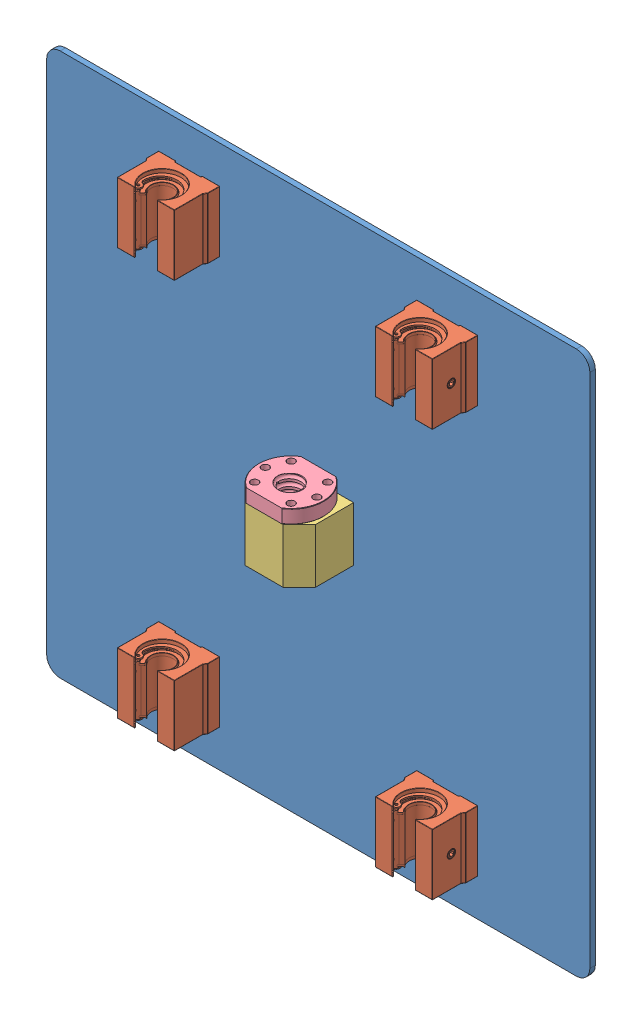
SolidWorks assembly Стол, configuration По умолчанию. Lengths in mm.
Overall size (400 400 44).
7 component instances, 4 part files, 12 mates.
Components (placement in the parent):
- Плита стола-1: Плита стола [По умолчанию] at (-52.7289 -0.1217 50.8505) size (400 400 4)
- SBR16UU-1: SBR16UU [По умолчанию] at (-147.7289 149.8783 74.8505) x (1 0 0) z (0 -1 0) size (45 32 45)
- SBR16UU-2: SBR16UU [По умолчанию] at (-147.7289 -150.1217 74.8505) x (1 0 0) z (0 -1 0) size (45 32 45)
- SBR16UU-3: SBR16UU [По умолчанию] at (42.2711 149.8783 74.8505) x (-1 0 0) z (0 1 0) size (45 32 45)
- SBR16UU-4: SBR16UU [По умолчанию] at (42.2711 -150.1217 74.8505) x (-1 0 0) z (0 1 0) size (45 32 45)
- bsh16-1: bsh16 [По умолчанию] at (-46.8326 19.8783 87.6733) x (1 0 0) z (0 -1 0) size (52 40 40)
- RM1605-1: RM1605 [RM1605] at (-52.7289 29.8783 74.8505) x (0 0 -1) z (0 1 0) size (40 48 48.86)
Mates (geometry in assembly coordinates):
- Концентричный1: concentric anti-aligned: cylinder of Плита стола-1 through (-163.7289 164.8783 54.8505) axis (0 0 1) radius 2.75; cylinder of SBR16UU-1 through (-163.7289 164.8783 54.8505) axis (0 0 -1) radius 2.1
- Концентричный2: concentric anti-aligned: cylinder of Плита стола-1 through (-131.7289 134.8783 54.8505) axis (0 0 1) radius 2.75; cylinder of SBR16UU-1 through (-131.7289 134.8783 54.8505) axis (0 0 -1) radius 2.1
- Совпадение1: coincident anti-aligned: plane of Плита стола-1 through (-52.7289 -0.1217 54.8505) normal (0 0 1); plane of SBR16UU-1 through (-170.2289 127.3783 54.8505) normal (0 0 -1)
- Концентричный3: concentric anti-aligned: cylinder of Плита стола-1 through (-131.7289 -165.1217 54.8505) axis (0 0 1) radius 2.75; cylinder of SBR16UU-2 through (-131.7289 -165.1217 54.8505) axis (0 0 -1) radius 2.1
- Концентричный4: concentric anti-aligned: cylinder of Плита стола-1 through (-163.7289 -165.1217 54.8505) axis (0 0 1) radius 2.75; cylinder of SBR16UU-2 through (-163.7289 -165.1217 54.8505) axis (0 0 -1) radius 2.1
- Совпадение2: coincident anti-aligned: plane of Плита стола-1 through (-52.7289 -0.1217 54.8505) normal (0 0 1); plane of SBR16UU-2 through (-170.2289 -172.6217 54.8505) normal (0 0 -1)
- Концентричный5: concentric: cylinder of Плита стола-1 through (-32.7289 11.8783 54.8505) axis (0 0 1) radius 2.75; cylinder of bsh16-1 through (-32.7289 11.8783 66.8505) axis (0 0 -1) radius 2.1
- Концентричный6: concentric: cylinder of Плита стола-1 through (-72.7289 -12.1217 54.8505) axis (0 0 1) radius 2.75; cylinder of bsh16-1 through (-72.7289 -12.1217 66.8505) axis (0 0 -1) radius 2.1
- Совпадение3: coincident anti-aligned: plane of Плита стола-1 through (-52.7289 -0.1217 54.8505) normal (0 0 1); plane of bsh16-1 through (-78.7289 -20.1217 54.8505) normal (0 0 -1)
- Концентричный7: concentric: cylinder of bsh16-1 through (-52.7289 -19.1217 74.8505) axis (0 1 0) radius 14; cylinder of RM1605-1 through (-52.7289 182.0367 74.8505) axis (0 -1 0) radius 13.9
- Концентричный8: concentric: cylinder of bsh16-1 through (-39.2938 9.8783 61.4155) axis (0 1 0) radius 2.1; cylinder of RM1605-1 through (-39.2938 224.0367 61.4155) axis (0 1 0) radius 2.75
- Совпадение4: coincident anti-aligned: plane of bsh16-1 through (-46.8326 19.8783 87.6733) normal (0 1 0); plane of RM1605-1 through (-76.7289 19.8783 74.8505) normal (0 -1 0)
